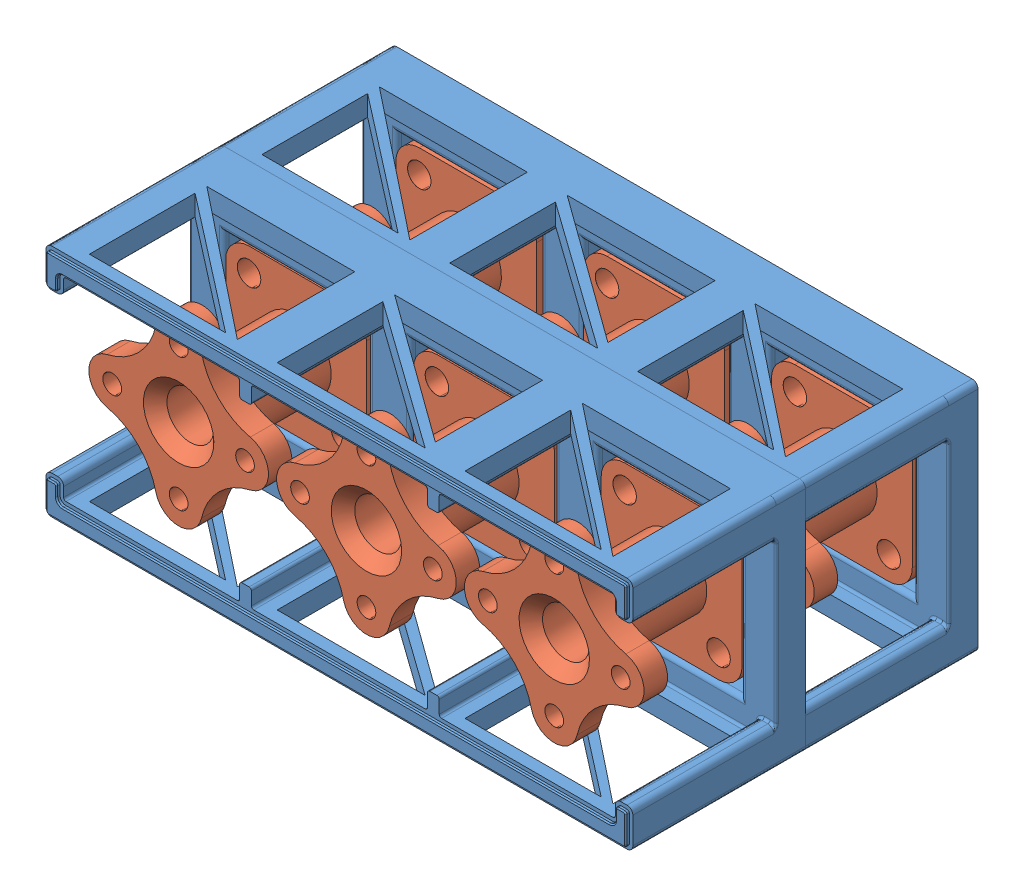
SolidWorks assembly Assieme2, configuration Default. Lengths in mm.
Overall size (536.57 216.57 297).
8 component instances, 2 part files, 6 mates.
Components (placement in the parent):
- vassoioX1_componibile-1: vassoioX1_componibile [Default] at (3.6852 17.6361 425.3224) size (500.32 200 150)
- vassoioX1_componibile-2: vassoioX1_componibile [Default] at (3.6852 17.6361 572.3224) size (500.32 200 150)
- X1.sat-1: X1.sat [Default] at (-157.3148 17.6361 575.3224) x (0.707107 -0.707107 0) z (0 0 1) size (153.14 153.14 120)
- X1.sat-2: X1.sat [Default] at (2.6852 17.6361 575.3224) x (0.707107 -0.707107 0) z (0 0 1) size (153.14 153.14 120)
- X1.sat-3: X1.sat [Default] at (162.6852 17.6361 575.3224) x (0.707107 -0.707107 0) z (0 0 1) size (153.14 153.14 120)
- X1.sat-4: X1.sat [Default] at (162.6852 17.6361 430.3224) x (0.707107 -0.707107 0) z (0 0 1) size (153.14 153.14 120)
- X1.sat-5: X1.sat [Default] at (2.6852 17.6361 430.3224) x (0.707107 -0.707107 0) z (0 0 1) size (153.14 153.14 120)
- X1.sat-6: X1.sat [Default] at (-157.3148 17.6361 430.3224) x (0.707107 -0.707107 0) z (0 0 1) size (153.14 153.14 120)
Mates (geometry in assembly coordinates):
- Coincidente1: coincident aligned: plane of vassoioX1_componibile-1 through (-246.3148 -82.3639 428.3224) normal (0 -1 0); plane of vassoioX1_componibile-2 through (-246.3148 -82.3639 575.3224) normal (0 -1 0)
- Coincidente2: coincident aligned: plane of vassoioX1_componibile-1 through (-246.3148 117.6361 428.3224) normal (-1 0 0); plane of vassoioX1_componibile-2 through (-246.3148 117.6361 575.3224) normal (-1 0 0)
- Coincidente3: coincident anti-aligned: plane of vassoioX1_componibile-1 through (3.6852 17.6361 572.3224) normal (0 0 1); plane of vassoioX1_componibile-2 through (3.6852 17.6361 572.3224) normal (0 0 -1)
- Distanza1: distance = 1 mm anti-aligned: plane of X1.sat-1 through (-217.3148 77.6361 595.3224) normal (-1 0 0); plane of vassoioX1_componibile-2 through (-216.3148 17.6361 597.3224) normal (1 0 0)
- Coincidente5: coincident anti-aligned: plane of vassoioX1_componibile-2 through (3.6852 17.6361 575.3224) normal (0 0 1); plane of X1.sat-1 through (-157.3148 17.6361 575.3224) normal (0 0 -1)
- Distanza2: distance = 1 mm anti-aligned: plane of X1.sat-1 through (-97.3148 77.6361 595.3224) normal (0 1 0); plane of vassoioX1_componibile-2 through (3.6852 78.6361 597.3224) normal (0 -1 0)
